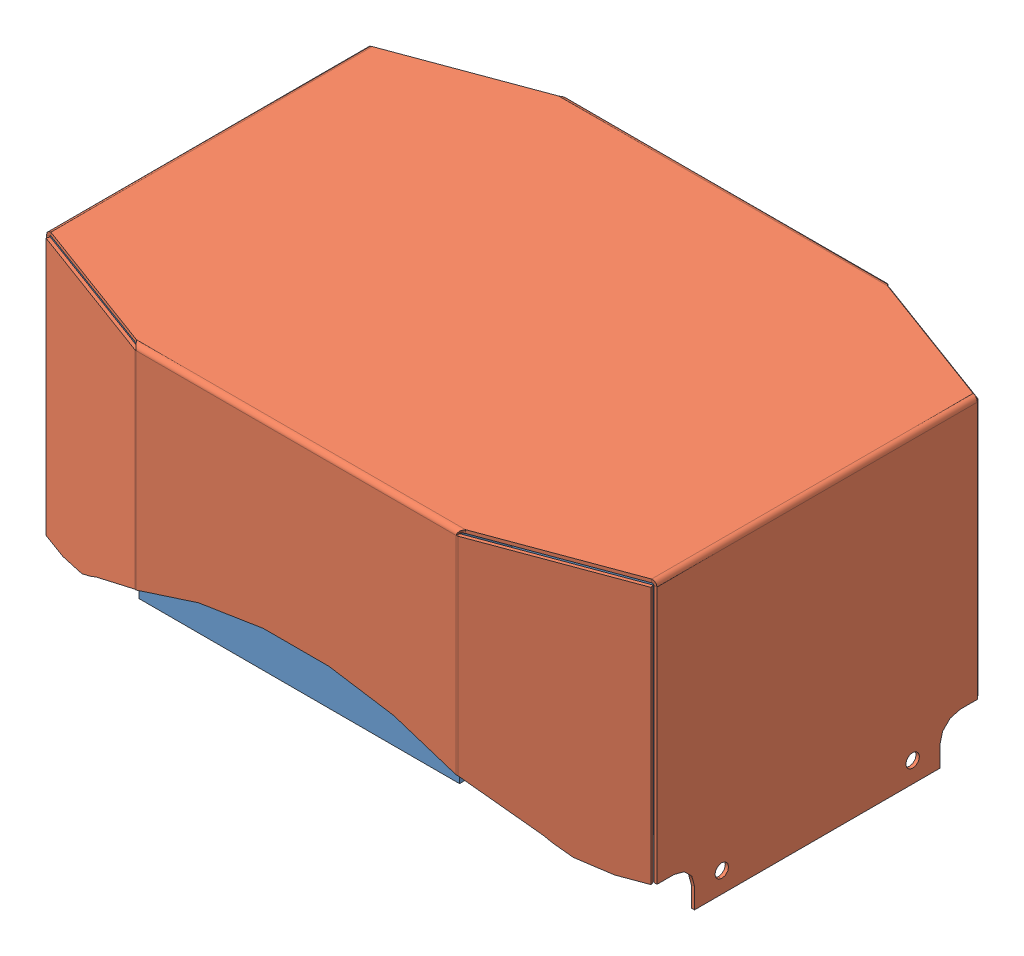
SolidWorks assembly battery_module, configuration Default. Lengths in mm.
Overall size (284.35 141.22 201.17).
6 component instances, 2 part files, 10 mates.
Components (placement in the parent):
- battery-1: battery [for_assembly] at origin size (149.22 101.6 66.04)
- battery-4: battery [for_assembly] at (0 0 66.04) size (149.22 101.6 66.04)
- battery-5: battery [for_assembly] at (0 0 132.08) size (149.22 101.6 66.04)
- battery-8: battery [for_assembly] at (107.6325 0 66.04) x (0 0 -1) z (1 0 0) size (149.22 101.6 66.04)
- battery-9: battery [for_assembly] at (-107.6325 0 66.04) x (0 0 1) z (-1 0 0) size (149.22 101.6 66.04)
- battery_tray-1: battery_tray [Default] at (0 101.6 66.04) x (-1 0 0) z (0 1 0) size (284.35 201.17 141.22)
Mates (geometry in assembly coordinates):
- Coincident4: coincident anti-aligned: plane of ?; plane of ?
- Coincident5: coincident aligned: plane of ?; plane of ?
- Coincident6: coincident anti-aligned: plane of ?; plane of ?
- Coincident7: coincident aligned: plane of ?; plane of ?
- Coincident8: coincident anti-aligned: plane of ?; plane of ?
- Coincident9: coincident anti-aligned: plane of ?; plane of ?
- InPlace1: in place: moOrthogonalPlaneRef_w of battery_tray-1
- Coincident10: coincident aligned: plane of ?; plane of ?
- Coincident11: coincident aligned: moOrthogonalPlaneRef_w of ?; plane of ?
- Coincident12: coincident anti-aligned: 
